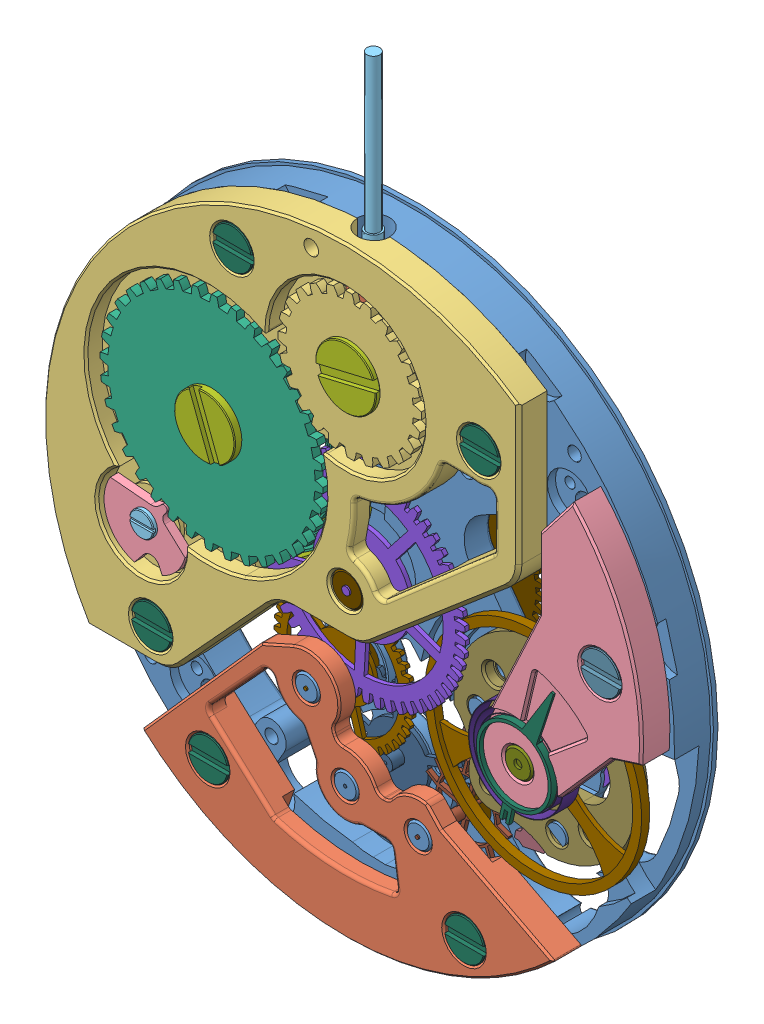
SolidWorks assembly watch movement eta-6497, configuration Default. Lengths in mm.
Overall size (37.71 45.6 5.66).
50 component instances, 38 part files, 89 mates.
Components (placement in the parent):
- MAIN_PLATE-scaled-1: MAIN_PLATE-scaled [Default] at origin size (37.71 36.6 2.78)
- TRAINWHEEL_BRIDGE-scaled-1: TRAINWHEEL_BRIDGE-scaled [Default] at (2.5344 36.3401 -7.4892) size (24.74 13.86 1.71)
- BARREL_BRIDGE-scaled-1: BARREL_BRIDGE-scaled [Default] at (14.8136 -19.5519 -6.5785) x (1 -0.000051 0) z (0 0 1) size (28.59 27.69 1.77)
- BALANCE_BRIDGE-scaled-1: BALANCE_BRIDGE-scaled [Default] at (-42.2984 -12.9016 -7.0972) x (1 0.000051 0) z (0 0 1) size (10.07 17.9 1.71)
- WINDING_STEM-scaled-1: WINDING_STEM-scaled [Default] at (10.0508 -68.8497 9.867) x (-0.408062 0 0.912954) z (-0.912954 0 -0.408062) size (1.01 15.96 1.01)
- RACHET_WHEEL-scaled-1: RACHET_WHEEL-scaled [Default] at (23.31 -20.3024 -7.9848) x (0.98772 -0.156233 0) z (0 0 1) size (13.44 13.44 0.48)
- RACHET_WHEEL_SCREW-scaled-1: RACHET_WHEEL_SCREW-scaled [Default] at (-12.6334 -35.0759 -7.5351) x (0.353105 -0.935584 0) z (0 0 1) size (3.66 3.66 2.6)
- DOUBLE_ROLLER-scaled-1: DOUBLE_ROLLER-scaled [Default] at (10.0823 -49.9696 1.6528) x (-0.365738 0.930718 0) z (0 0 1) size (5.37 5.37 2.36)
- BALANCE_WHEEL-scaled-1: BALANCE_WHEEL-scaled [Default] at (-30.3404 11.2366 -4.9178) x (0.999946 0.0104 0) z (0 0 1) size (13.07 13.07 0.49)
- DRIVER_CANNON_PINION-scaled-1: DRIVER_CANNON_PINION-scaled [Default] at (0.9212 -1.272 1.901) x (0.943007 0.332774 0) z (0 0 1) size (3.16 3.16 1.95)
- SETTING_LEVER_JUMPER-scaled-1: SETTING_LEVER_JUMPER-scaled [Default] at (-11.993 -30.3688 2.2117) x (0.999994 -0.00349 0) z (0 0 1) size (15.05 13.39 0.24)
- hour hand-1: hour hand [Default] at (0.9212 -1.272 2.9686) x (0.624696 0.780868 0) z (-0.780868 0.624696 0) size (13.45 0.48 2.7)
- minute hand-1: minute hand [Default] at (0.9212 -1.272 2.6686) x (0.738173 -0.674611 0) z (0.674611 0.738173 0) size (17.1 0.76 2.7)
- SETTING_LEVER-scaled-1: SETTING_LEVER-scaled [Default] at (11.0066 -49.5518 1.4696) x (1 -0.000174 0) z (0 0 1) size (6.14 4.36 0.49)
- REGULATOR-scaled-1: REGULATOR-scaled [Default] at (-30.7962 10.7464 -8.6033) size (4.64 8.34 0.37)
- JEWEL_BALANCE-scaled-1: JEWEL_BALANCE-scaled [Default] at (-30.1637 11.6689 -7.8137) size (1.71 1.71 0.37)
- hour wheel-40T-1: hour wheel-40T [Default] at (0.9212 -1.272 3.8344) x (0.652479 -0.757807 0) z (0.757807 0.652479 0) size (8.3 1.22 8.3)
- gear-2-1: gear-2 [Default] at (5.4157 1.075 4.2004) x (0.460007 -0.887915 0) z (0.887915 0.460007 0) size (8.2 0.64 8.2)
- 16T gear-1: 16T gear [Default] at (3.4604 6.3566 4.3224) x (0.960913 0.27685 0) z (-0.27685 0.960913 0) size (3.6 0.36 3.6)
- 16T gear-2: 16T gear [Default] at (0.9301 8.6353 4.3224) x (0.919979 0.391968 0) z (-0.391968 0.919979 0) size (3.6 0.36 3.6)
- SLIDING_PINION-scaled-1: SLIDING_PINION-scaled [Default] at (-5.9207 -44.3189 -1.5067) x (0.729303 0 -0.684191) z (0.684191 0 0.729303) size (2.32 2.18 2.32)
- CROWN_WHEEL-scaled-1: CROWN_WHEEL-scaled [Default] at (-12.6475 -33.666 -7.9811) x (0.955246 -0.295813 0) z (0 0 1) size (8.64 8.64 0.48)
- RACHET_WHEEL_SCREW-scaled-2: RACHET_WHEEL_SCREW-scaled [Default] at (38.2616 -0.2875 -7.7056) x (0.973191 0.229999 0) z (0 0 1) size (3.66 3.66 2.6)
- CLICK-scaled-1: CLICK-scaled [Default] at (36.7009 18.147 -7.9936) x (0.980467 0.196685 0) z (0 0 1) size (4.7 4.11 0.49)
- CLICK_SCREW-scaled-1: CLICK_SCREW-scaled [Default] at (38.9217 6.9981 -8.1965) size (1.46 1.46 1.76)
- main spring-1: main spring [Default] at (-7.394 3.1296 5.3464) x (0.236309 0.971678 0) z (-0.971678 0.236309 0) size (13.86 1.21 13.98)
- mainspring barrel-1: mainspring barrel [Default] at (-7.3704 3.2301 5.7464) x (-0.351757 0.936092 0) z (-0.936092 -0.351757 0) size (14.6 3.11 14.6)
- CENTER_WHEEL-scaled-1: CENTER_WHEEL-scaled [Default] at (0.9258 -1.2745 -6.2095) x (-0.613631 -0.789593 0) z (0 0 1) size (12.44 12.44 3.43)
- THIRD_WHEEL-scaled-1: THIRD_WHEEL-scaled [Default] at (-8.1014 18.875 -0.7426) x (0.821405 0.570345 0) z (0 0 1) size (8.36 8.35 4.26)
- SECOND_WHEEL-scaled-1: SECOND_WHEEL-scaled [Default] at (-33.5485 11.8646 -2.35) x (0.560513 0.828146 0) z (0 0 1) size (8.36 8.35 4.13)
- ESCAPE_WHEEL-scaled-1: ESCAPE_WHEEL-scaled [Default] at (51.8113 -4.9013 -0.1956) x (-0.243002 -0.970026 0) z (0 0 1) size (5.04 5.04 4.35)
- PALLET_BRIDGE-scaled-1: PALLET_BRIDGE-scaled [Default] at (-30.2397 10.7159 -2.3711) x (0.999995 -0.003169 0) z (0 0 1) size (10.97 10.97 1.46)
- PALLET_FORK-scaled-1: PALLET_FORK-scaled [Default] at (-24.7287 18.9965 0.4657) x (0.990636 0.136529 0) z (0 0 1) size (5.68 6.43 0.24)
- BALANCE_SCREW-scaled-1: BALANCE_SCREW-scaled [Default] at (-46.6067 -11.7285 -5.7239) size (2.44 2.44 3.57)
- BARREL_BRIDGE_SCREW-scaled-1: BARREL_BRIDGE_SCREW-scaled [Default] at (56.8731 41.5159 -5.7239) size (2.44 2.44 3.57)
- BARREL_BRIDGE_SCREW-scaled-2: BARREL_BRIDGE_SCREW-scaled [Default] at (42.0185 44.6227 -5.7239) size (2.44 2.44 3.57)
- BARREL_BRIDGE_SCREW-scaled-3: BARREL_BRIDGE_SCREW-scaled [Default] at (37.1325 22.4971 -5.7239) size (2.44 2.44 3.57)
- BARREL_BRIDGE_SCREW-scaled-4: BARREL_BRIDGE_SCREW-scaled [Default] at (55.983 15.5654 -5.7239) size (2.44 2.44 3.57)
- BARREL_BRIDGE_SCREW-scaled-5: BARREL_BRIDGE_SCREW-scaled [Default] at (40.5622 17.2734 -5.7239) size (2.44 2.44 3.57)
- bw shaft-1: bw shaft [Default] at (10.9539 -5.4487 3.9733) x (0.664459 -0.747325 0) z (-0.747325 -0.664459 0) size (0.49 3 0.49)
- balance spring-1: balance spring [Default] at (10.7982 -5.4568 7.0064) x (0.980374 -0.197147 0) z (-0.197147 -0.980374 0) size (5.76 1.01 5.91)
- JEWEL_MAIN-scaled-5: JEWEL_MAIN-scaled [Default] at (0.9205 -1.2722 -9.0684) size (1.95 1.95 0.37)
- JEWEL_MAIN-scaled-6: JEWEL_MAIN-scaled [Default] at (5.325 -11.8619 19.7871) x (0.901008 -0.433803 0) z (0 0 -1) size (1.95 1.95 0.37)
- JEWEL_MAIN-scaled-7: JEWEL_MAIN-scaled [Default] at (0.9309 -11.4243 19.7871) x (-0.858855 0.512218 0) z (0 0 -1) size (1.95 1.95 0.37)
- JEWEL_MAIN-scaled-8: JEWEL_MAIN-scaled [Default] at (-1.4055 -7.4875 19.7871) x (-0.953158 -0.302473 0) z (0 0 -1) size (1.95 1.95 0.37)
- JEWEL_BALANCE-scaled-3: JEWEL_BALANCE-scaled [Default] at (11.1063 -53.465 18.2884) x (0.308361 0.95127 0) z (0 0 -1) size (1.71 1.71 0.37)
- jewel-trainwheel-4: jewel-trainwheel [Default] at (-1.4055 -7.4875 7.4944) x (0.887598 0.460619 0) z (0 0 -1) size (1.5 1.5 0.4)
- jewel-trainwheel-5: jewel-trainwheel [Default] at (0.9308 -11.4243 7.4944) x (0.966485 0.256724 0) z (0 0 -1) size (1.5 1.5 0.4)
- jewel-trainwheel-6: jewel-trainwheel [Default] at (5.325 -11.8619 7.4944) x (0.902621 0.430435 0) z (0 0 -1) size (1.5 1.5 0.4)
- shaft-2-1: shaft-2 [Default] at (7.4813 -9.0714 5.3464) x (-0.704887 0.70932 0) z (-0.70932 -0.704887 0) size (0.4 2 0.4)
Mates (geometry in assembly coordinates):
- Coincident1: coincident anti-aligned: plane of MAIN_PLATE-scaled-1 through (-11.904 -5.8961 5.7864) normal (0 0 1); plane of BARREL_BRIDGE-scaled-1 through (-17.3872 -10.8229 5.7864) normal (0 0 -1)
- Concentric1: concentric aligned: cylinder of MAIN_PLATE-scaled-1 through (8.9738 10.0757 4.0784) axis (0 0 1) radius 0.4392; cylinder of BARREL_BRIDGE-scaled-1 through (8.9731 10.0759 5.7864) axis (0 0 1) radius 0.4392
- Concentric2: concentric aligned: cylinder of MAIN_PLATE-scaled-1 through (-5.8815 13.1827 4.0784) axis (0 0 1) radius 0.4821; cylinder of BARREL_BRIDGE-scaled-1 through (-5.8815 13.1827 5.7864) axis (0 0 1) radius 0.4392
- Coincident2: coincident anti-aligned: plane of MAIN_PLATE-scaled-1 through (-17.4172 -19.5383 5.7864) normal (0 0 1); plane of TRAINWHEEL_BRIDGE-scaled-1 through (-11.3594 -18.3746 5.7864) normal (0 0 -1)
- Concentric3: concentric aligned: cylinder of MAIN_PLATE-scaled-1 through (-7.3378 -14.1666 3.3464) axis (0 0 1) radius 0.4392; cylinder of TRAINWHEEL_BRIDGE-scaled-1 through (-7.3378 -14.1666 5.7864) axis (0 0 1) radius 0.4392
- Concentric4: concentric aligned: cylinder of MAIN_PLATE-scaled-1 through (8.083 -15.8746 3.3464) axis (0 0 1) radius 0.4392; cylinder of TRAINWHEEL_BRIDGE-scaled-1 through (8.083 -15.8746 5.7864) axis (0 0 1) radius 0.4392
- Coincident3: coincident anti-aligned: plane of MAIN_PLATE-scaled-1 through (-11.904 -5.8961 5.7864) normal (0 0 1); plane of BALANCE_BRIDGE-scaled-1 through (11.6238 -2.1978 5.7864) normal (0 0 -1)
- Concentric5: concentric aligned: cylinder of MAIN_PLATE-scaled-1 through (16.2609 2.104 3.3464) axis (0 0 1) radius 0.4518; cylinder of BALANCE_BRIDGE-scaled-1 through (16.2606 2.1034 5.7864) axis (0 0 1) radius 0.7823
- Concentric7: concentric aligned: cylinder of WINDING_STEM-scaled-1 through (0.9212 14.8036 5.7864) axis (0 1 0) radius 0.4854; cylinder of MAIN_PLATE-scaled-1 through (0.9212 14.5407 5.7864) axis (0 1 0) radius 0.976
- Concentric8: concentric anti-aligned: cylinder of BARREL_BRIDGE-scaled-1 through (-7.3704 3.2301 5.7864) axis (0 0 1) radius 1.2007; cylinder of RACHET_WHEEL-scaled-1 through (-7.3704 3.2301 7.2424) axis (0 0 -1) radius 1.8
- Concentric9: concentric aligned: cylinder of RACHET_WHEEL-scaled-1 through (-7.3704 3.2301 7.2424) axis (0 0 -1) radius 1.8; cylinder of RACHET_WHEEL_SCREW-scaled-1 through (-7.3704 3.2301 7.6209) axis (0 0 -1) radius 1.83
- Concentric10: concentric anti-aligned: cylinder of MAIN_PLATE-scaled-1 through (10.9539 -5.4487 4.0784) axis (0 0 -1) radius 0.8396; cylinder of DOUBLE_ROLLER-scaled-1 through (10.9539 -5.4487 3.8694) axis (0 0 1) radius 0.6665
- Concentric11: concentric aligned: cylinder of DOUBLE_ROLLER-scaled-1 through (10.9539 -5.4487 5.0443) axis (0 0 1) radius 1.1591; cylinder of BALANCE_WHEEL-scaled-1 through (10.9539 -5.4487 5.7221) axis (0 0 1) radius 0.2029
- Coincident6: coincident anti-aligned: plane of DOUBLE_ROLLER-scaled-1 through (12.4742 -6.1116 5.7221) normal (0 0 1); plane of BALANCE_WHEEL-scaled-1 through (4.4084 -12.1318 5.7221) normal (0 0 -1)
- Concentric12: concentric aligned: cylinder of MAIN_PLATE-scaled-1 through (0.9212 -1.272 4.3224) axis (0 0 1) radius 0.5072; cylinder of DRIVER_CANNON_PINION-scaled-1 through (0.9212 -1.272 3.6531) axis (0 0 1) radius 0.6539
- Coincident7: coincident anti-aligned: plane of MAIN_PLATE-scaled-1 through (2.9241 -3.275 4.3224) normal (0 0 -1); plane of DRIVER_CANNON_PINION-scaled-1 through (2.9588 -2.2466 4.3224) normal (0 0 1)
- Concentric15: concentric aligned: cylinder of MAIN_PLATE-scaled-1 through (6.5642 7.0405 3.8344) axis (0 0 1) radius 0.4707; circle of SETTING_LEVER_JUMPER-scaled-1
- Coincident9: coincident anti-aligned: plane of MAIN_PLATE-scaled-1 through (10.0896 3.6434 3.8344) normal (0 0 -1); plane of SETTING_LEVER_JUMPER-scaled-1 through (11.7473 1.2487 3.8344) normal (0 0 1)
- Concentric16: concentric anti-aligned: cylinder of MAIN_PLATE-scaled-1 through (10.9539 -5.4487 4.0784) axis (0 0 -1) radius 0.8396; cylinder of BALANCE_BRIDGE-scaled-1 through (10.9539 -5.4487 6.7624) axis (0 0 1) radius 0.859
- Concentric18: concentric aligned: cylinder of DRIVER_CANNON_PINION-scaled-1 through (0.9212 -1.272 2.3686) axis (0 0 1) radius 0.3411; cylinder of minute hand-1 through (0.9212 -1.272 2.3686) axis (0 0 1) radius 0.34
- Coincident11: coincident aligned: plane of DRIVER_CANNON_PINION-scaled-1 through (1.3616 -1.4826 2.3686) normal (0 0 -1); plane of minute hand-1 through (11.9104 -10.8013 2.3686) normal (0 0 -1)
- Coincident12: coincident anti-aligned: plane of SETTING_LEVER_JUMPER-scaled-1 through (11.7473 1.2487 3.8344) normal (0 0 1); plane of SETTING_LEVER-scaled-1 through (-1.8442 14.4894 3.8344) normal (0 0 -1)
- Concentric19: concentric anti-aligned: cylinder of MAIN_PLATE-scaled-1 through (-1.1083 15.6219 4.0784) axis (0 0 1) radius 0.4527; cylinder of SETTING_LEVER-scaled-1 through (-1.1083 15.6219 4.0784) axis (0 0 -1) radius 0.488
- Coincident13: coincident anti-aligned: plane of BALANCE_BRIDGE-scaled-1 through (11.5699 -3.6889 7.2504) normal (0 0 1); plane of REGULATOR-scaled-1 through (12.7329 -1.6663 7.2504) normal (0 0 -1)
- Concentric20: concentric aligned: cylinder of BALANCE_BRIDGE-scaled-1 through (10.9539 -5.4487 6.7624) axis (0 0 1) radius 0.859; cylinder of REGULATOR-scaled-1 through (10.9539 -5.4487 7.0064) axis (0 0 1) radius 2.074
- Concentric21: concentric aligned: cylinder of BALANCE_BRIDGE-scaled-1 through (10.9539 -5.4487 6.7624) axis (0 0 1) radius 0.859; cylinder of JEWEL_BALANCE-scaled-1 through (10.9539 -5.4487 6.7624) axis (0 0 1) radius 0.854
- Coincident14: coincident aligned: plane of BALANCE_BRIDGE-scaled-1 through (8.8552 -7.5477 7.1284) normal (0 0 1); plane of JEWEL_BALANCE-scaled-1 through (10.9539 -5.4487 7.1284) normal (0 0 1)
- Coincident15: coincident anti-aligned: plane of MAIN_PLATE-scaled-1 through (5.2754 -6.0483 3.8344) normal (0 0 -1); plane of hour wheel-40T-1 through (0.9212 -1.272 3.8344) normal (0 0 1)
- Concentric22: concentric anti-aligned: cylinder of DRIVER_CANNON_PINION-scaled-1 through (0.9212 -1.272 3.6531) axis (0 0 1) radius 0.6539; cylinder of hour wheel-40T-1 through (0.9212 -1.272 3.8344) axis (0 0 -1) radius 0.73
- Coincident16: coincident anti-aligned: plane of MAIN_PLATE-scaled-1 through (9.7641 -3.2735 4.2004) normal (0 0 -1); plane of gear-2-1 through (5.4157 1.075 4.2004) normal (0 0 1)
- Concentric23: concentric aligned: cylinder of MAIN_PLATE-scaled-1 through (5.4157 1.075 4.2004) axis (0 0 -1) radius 0.6653; cylinder of gear-2-1 through (5.4157 1.075 4.2004) axis (0 0 -1) radius 0.5
- Concentric24: concentric aligned: cylinder of hour hand-1 through (0.9212 -1.272 2.6686) axis (0 0 1) radius 0.93; cylinder of hour wheel-40T-1 through (0.9212 -1.272 2.6144) axis (0 0 1) radius 0.93
- Concentric25: concentric aligned: cylinder of MAIN_PLATE-scaled-1 through (3.4604 6.3566 4.3224) axis (0 0 -1) radius 0.4392; cylinder of 16T gear-1 through (3.4604 6.3566 4.3224) axis (0 0 -1) radius 0.44
- Coincident17: coincident anti-aligned: plane of MAIN_PLATE-scaled-1 through (5.62 4.2013 4.3224) normal (0 0 -1); plane of 16T gear-1 through (3.4604 6.3566 4.3224) normal (0 0 1)
- Concentric26: concentric aligned: cylinder of MAIN_PLATE-scaled-1 through (0.9301 8.6353 4.3224) axis (0 0 -1) radius 0.4392; cylinder of 16T gear-2 through (0.9301 8.6353 4.3224) axis (0 0 -1) radius 0.44
- Coincident18: coincident aligned: plane of 16T gear-1 through (3.4604 6.3566 3.9624) normal (0 0 -1); plane of 16T gear-2 through (0.9301 8.6353 3.9624) normal (0 0 -1)
- Concentric27: concentric aligned: cylinder of WINDING_STEM-scaled-1 through (0.9212 11.008 5.7864) axis (0 1 0) radius 0.2436; cylinder of SLIDING_PINION-scaled-1 through (0.9212 12.0782 5.7864) axis (0 1 0) radius 0.342
- Concentric28: concentric aligned: cylinder of BARREL_BRIDGE-scaled-1 through (0.9491 9.8525 5.7864) axis (0 0 1) radius 0.622; cylinder of CROWN_WHEEL-scaled-1 through (0.9491 9.8525 6.7624) axis (0 0 1) radius 1.0841
- Coincident19: coincident aligned: plane of RACHET_WHEEL-scaled-1 through (-15.1485 -2.4235 7.2424) normal (0 0 1); plane of CROWN_WHEEL-scaled-1 through (0.9491 9.8525 7.2424) normal (0 0 1)
- Coincident20: coincident anti-aligned: plane of BARREL_BRIDGE-scaled-1 through (-12.8023 -2.2021 6.7624) normal (0 0 1); plane of RACHET_WHEEL-scaled-1 through (-15.1485 -2.4235 6.7624) normal (0 0 -1)
- Concentric29: concentric anti-aligned: cylinder of BARREL_BRIDGE-scaled-1 through (0.9491 9.8525 5.7864) axis (0 0 1) radius 0.622; cylinder of RACHET_WHEEL_SCREW-scaled-2 through (0.9491 9.8525 7.0112) axis (0 0 -1) radius 0.488
- Concentric30: concentric aligned: cylinder of BARREL_BRIDGE-scaled-1 through (-11.3446 -3.9406 6.7624) axis (0 0 1) radius 0.6582; cylinder of CLICK-scaled-1 through (-11.3446 -3.9406 6.7624) axis (0 0 1) radius 0.7292
- Coincident21: coincident anti-aligned: plane of BARREL_BRIDGE-scaled-1 through (-13.004 -5.5998 6.7624) normal (0 0 1); plane of CLICK-scaled-1 through (-11.4397 -4.3432 6.7624) normal (0 0 -1)
- Concentric31: concentric anti-aligned: cylinder of BARREL_BRIDGE-scaled-1 through (-11.3446 -3.9406 5.7864) axis (0 0 1) radius 0.4142; cylinder of CLICK_SCREW-scaled-1 through (-11.3446 -3.9406 6.5709) axis (0 0 -1) radius 0.2087
- Coincident22: coincident anti-aligned: plane of BARREL_BRIDGE-scaled-1 through (-12.0107 -4.6066 7.2504) normal (0 0 1); plane of CLICK_SCREW-scaled-1 through (-10.8742 -3.9406 7.2504) normal (0 0 -1)
- Concentric32: concentric anti-aligned: cylinder of BARREL_BRIDGE-scaled-1 through (-7.3704 3.2301 5.7864) axis (0 0 1) radius 1.2007; cylinder of mainspring barrel-1 through (-7.3704 3.2301 7.3464) axis (0 0 -1) radius 1.2
- Distance1: distance = 0.9 mm aligned: plane of mainspring barrel-1 through (-7.3704 3.2301 4.2464) normal (0 0 -1); plane of MAIN_PLATE-scaled-1 through (-17.5984 -19.7916 3.3464) normal (0 0 -1)
- Coincident27: coincident: line of main spring-1 through (-14.1958 4.7838 4.3964) axis (0 0 1); cylinder of mainspring barrel-1 through (-7.3704 3.2301 5.7464) axis (0 0 -1) radius 7
- Coincident28: coincident anti-aligned: plane of main spring-1 through (-14.0986 4.7602 4.3464) normal (0 0 -1); plane of mainspring barrel-1 through (-7.3704 3.2301 4.3464) normal (0 0 1)
- Concentric33: concentric aligned: cylinder of BARREL_BRIDGE-scaled-1 through (0.9205 -1.2722 7.3724) axis (0 0 -1) radius 0.976; cylinder of CENTER_WHEEL-scaled-1 through (0.9205 -1.2722 6.2275) axis (0 0 -1) radius 1.22
- Concentric35: concentric anti-aligned: cylinder of TRAINWHEEL_BRIDGE-scaled-1 through (-1.4055 -7.4875 7.3724) axis (0 0 -1) radius 0.732; cylinder of THIRD_WHEEL-scaled-1 through (-1.4055 -7.4875 6.6959) axis (0 0 1) radius 0.4398
- Concentric43: concentric anti-aligned: cylinder of TRAINWHEEL_BRIDGE-scaled-1 through (0.9308 -11.4243 7.3724) axis (0 0 -1) radius 0.732; cylinder of SECOND_WHEEL-scaled-1 through (0.9308 -11.4243 4.3481) axis (0 0 1) radius 0.4392
- Concentric44: concentric aligned: cylinder of TRAINWHEEL_BRIDGE-scaled-1 through (5.325 -11.8619 7.3724) axis (0 0 -1) radius 0.732; cylinder of ESCAPE_WHEEL-scaled-1 through (5.325 -11.8619 5.9361) axis (0 0 -1) radius 0.3281
- Concentric45: concentric aligned: cylinder of MAIN_PLATE-scaled-1 through (7.8501 -3.1743 3.3464) axis (0 0 1) radius 0.4848; cylinder of PALLET_BRIDGE-scaled-1 through (7.8501 -3.1743 4.7567) axis (0 0 1) radius 0.488
- Concentric47: concentric aligned: cylinder of PALLET_BRIDGE-scaled-1 through (7.4813 -9.0714 4.7567) axis (0 0 1) radius 0.488; cylinder of PALLET_FORK-scaled-1 through (7.4813 -9.0714 4.3437) axis (0 0 1) radius 0.2031
- Concentric48: concentric anti-aligned: cylinder of MAIN_PLATE-scaled-1 through (16.2609 2.104 3.3464) axis (0 0 1) radius 0.4518; cylinder of BALANCE_SCREW-scaled-1 through (16.2609 2.104 5.2203) axis (0 0 -1) radius 0.6196
- Coincident37: coincident anti-aligned: plane of BALANCE_BRIDGE-scaled-1 through (15.026 0.8687 6.2744) normal (0 0 1); plane of BALANCE_SCREW-scaled-1 through (17.1807 2.104 6.2744) normal (0 0 -1)
- Concentric49: concentric anti-aligned: cylinder of BARREL_BRIDGE-scaled-1 through (8.9731 10.0759 5.7864) axis (0 0 1) radius 0.4392; cylinder of BARREL_BRIDGE_SCREW-scaled-1 through (8.9731 10.0759 5.2203) axis (0 0 -1) radius 0.6196
- Coincident38: coincident anti-aligned: plane of BARREL_BRIDGE-scaled-1 through (7.7384 8.8413 6.2744) normal (0 0 1); plane of BARREL_BRIDGE_SCREW-scaled-1 through (9.8929 10.0759 6.2744) normal (0 0 -1)
- Concentric50: concentric anti-aligned: cylinder of BARREL_BRIDGE-scaled-1 through (-5.8815 13.1827 5.7864) axis (0 0 1) radius 0.4392; cylinder of BARREL_BRIDGE_SCREW-scaled-2 through (-5.8815 13.1827 5.2203) axis (0 0 -1) radius 0.6196
- Coincident39: coincident anti-aligned: plane of BARREL_BRIDGE-scaled-1 through (-7.1162 11.9482 6.2744) normal (0 0 1); plane of BARREL_BRIDGE_SCREW-scaled-2 through (-4.9617 13.1827 6.2744) normal (0 0 -1)
- Concentric51: concentric anti-aligned: cylinder of BARREL_BRIDGE-scaled-1 through (-10.7675 -8.9429 5.7864) axis (0 0 1) radius 0.4392; cylinder of BARREL_BRIDGE_SCREW-scaled-3 through (-10.7675 -8.9429 5.2203) axis (0 0 -1) radius 0.6196
- Coincident40: coincident anti-aligned: plane of BARREL_BRIDGE-scaled-1 through (-12.0022 -10.1775 6.2744) normal (0 0 1); plane of BARREL_BRIDGE_SCREW-scaled-3 through (-9.8477 -8.9429 6.2744) normal (0 0 -1)
- Concentric52: concentric anti-aligned: cylinder of TRAINWHEEL_BRIDGE-scaled-1 through (8.083 -15.8746 5.7864) axis (0 0 1) radius 0.4392; cylinder of BARREL_BRIDGE_SCREW-scaled-4 through (8.083 -15.8746 5.2203) axis (0 0 -1) radius 0.6196
- Coincident41: coincident anti-aligned: plane of TRAINWHEEL_BRIDGE-scaled-1 through (6.8484 -17.1092 6.2744) normal (0 0 1); plane of BARREL_BRIDGE_SCREW-scaled-4 through (9.0028 -15.8746 6.2744) normal (0 0 -1)
- Concentric53: concentric anti-aligned: cylinder of TRAINWHEEL_BRIDGE-scaled-1 through (-7.3378 -14.1666 5.7864) axis (0 0 1) radius 0.4392; cylinder of BARREL_BRIDGE_SCREW-scaled-5 through (-7.3378 -14.1666 5.2203) axis (0 0 -1) radius 0.6196
- Coincident42: coincident anti-aligned: plane of TRAINWHEEL_BRIDGE-scaled-1 through (-8.5724 -15.4012 6.2744) normal (0 0 1); plane of BARREL_BRIDGE_SCREW-scaled-5 through (-6.418 -14.1666 6.2744) normal (0 0 -1)
- Concentric55: concentric anti-aligned: cylinder of JEWEL_BALANCE-scaled-1 through (10.9539 -5.4487 6.7624) axis (0 0 1) radius 0.244; cylinder of bw shaft-1 through (10.9539 -5.4487 6.9733) axis (0 0 -1) radius 0.245
- Coincident44: coincident anti-aligned: plane of hour hand-1 through (7.4484 7.3814 2.6686) normal (0 0 -1); plane of minute hand-1 through (11.9104 -10.8013 2.6686) normal (0 0 1)
- Coincident45: coincident anti-aligned: plane of REGULATOR-scaled-1 through (11.5537 -4.3136 7.0064) normal (0 0 -1); plane of balance spring-1 through (10.2068 -8.3979 7.0064) normal (0 0 1)
- Coincident46: coincident aligned: plane of REGULATOR-scaled-1 through (10.1959 -8.4477 7.2504) normal (0.977112 -0.212723 0); plane of balance spring-1 through (10.21 -8.3833 7.0064) normal (0.977112 -0.212723 0)
- Concentric57: concentric anti-aligned: cylinder of BARREL_BRIDGE-scaled-1 through (0.9205 -1.2722 7.3724) axis (0 0 -1) radius 0.976; cylinder of JEWEL_MAIN-scaled-5 through (0.9205 -1.2722 7.0064) axis (0 0 1) radius 0.976
- Concentric58: concentric aligned: cylinder of MAIN_PLATE-scaled-1 through (5.325 -11.8619 4.3464) axis (0 0 -1) radius 0.975; cylinder of JEWEL_MAIN-scaled-6 through (5.325 -11.8619 3.7124) axis (0 0 -1) radius 0.976
- Coincident48: coincident aligned: plane of MAIN_PLATE-scaled-1 through (-17.5984 -19.7916 3.3464) normal (0 0 -1); plane of JEWEL_MAIN-scaled-6 through (5.325 -11.8619 3.3464) normal (0 0 -1)
- Concentric60: concentric aligned: cylinder of MAIN_PLATE-scaled-1 through (0.9309 -11.4243 4.3464) axis (0 0 -1) radius 0.975; cylinder of JEWEL_MAIN-scaled-7 through (0.9309 -11.4243 3.7124) axis (0 0 -1) radius 0.976
- Coincident49: coincident aligned: plane of MAIN_PLATE-scaled-1 through (-17.5984 -19.7916 3.3464) normal (0 0 -1); plane of JEWEL_MAIN-scaled-7 through (0.9309 -11.4243 3.3464) normal (0 0 -1)
- Concentric61: concentric aligned: cylinder of MAIN_PLATE-scaled-1 through (-1.4055 -7.4875 4.3464) axis (0 0 -1) radius 0.975; cylinder of JEWEL_MAIN-scaled-8 through (-1.4055 -7.4875 3.7124) axis (0 0 -1) radius 0.976
- Coincident50: coincident aligned: plane of MAIN_PLATE-scaled-1 through (-17.5984 -19.7916 3.3464) normal (0 0 -1); plane of JEWEL_MAIN-scaled-8 through (-1.4055 -7.4875 3.3464) normal (0 0 -1)
- Concentric63: concentric aligned: cylinder of MAIN_PLATE-scaled-1 through (7.502 -9.0726 5.8415) axis (0 0 -1) radius 0.855; cylinder of JEWEL_BALANCE-scaled-3 through (7.502 -9.0726 3.7124) axis (0 0 -1) radius 0.854
- Coincident51: coincident aligned: plane of MAIN_PLATE-scaled-1 through (-17.5984 -19.7916 3.3464) normal (0 0 -1); plane of JEWEL_BALANCE-scaled-3 through (7.502 -9.0726 3.3464) normal (0 0 -1)
- Concentric65: concentric anti-aligned: cylinder of TRAINWHEEL_BRIDGE-scaled-1 through (-1.4055 -7.4875 7.3724) axis (0 0 -1) radius 0.732; cylinder of jewel-trainwheel-4 through (-1.4055 -7.4875 7.0944) axis (0 0 1) radius 0.75
- Coincident52: coincident aligned: plane of TRAINWHEEL_BRIDGE-scaled-1 through (-11.2874 -19.3119 7.4944) normal (0 0 1); plane of jewel-trainwheel-4 through (-1.4055 -7.4875 7.4944) normal (0 0 1)
- Concentric66: concentric anti-aligned: cylinder of TRAINWHEEL_BRIDGE-scaled-1 through (0.9308 -11.4243 7.3724) axis (0 0 -1) radius 0.732; cylinder of jewel-trainwheel-5 through (0.9308 -11.4243 7.0944) axis (0 0 1) radius 0.75
- Coincident53: coincident aligned: plane of TRAINWHEEL_BRIDGE-scaled-1 through (-11.2874 -19.3119 7.4944) normal (0 0 1); plane of jewel-trainwheel-5 through (0.9308 -11.4243 7.4944) normal (0 0 1)
- Concentric67: concentric anti-aligned: cylinder of TRAINWHEEL_BRIDGE-scaled-1 through (5.325 -11.8619 7.3724) axis (0 0 -1) radius 0.732; cylinder of jewel-trainwheel-6 through (5.325 -11.8619 7.0944) axis (0 0 1) radius 0.75
- Coincident54: coincident aligned: plane of TRAINWHEEL_BRIDGE-scaled-1 through (-11.2874 -19.3119 7.4944) normal (0 0 1); plane of jewel-trainwheel-6 through (5.325 -11.8619 7.4944) normal (0 0 1)
- Concentric68: concentric aligned: cylinder of PALLET_FORK-scaled-1 through (7.4813 -9.0714 4.3437) axis (0 0 1) radius 0.2031; cylinder of shaft-2-1 through (7.4813 -9.0714 3.3464) axis (0 0 1) radius 0.2
- Concentric69: concentric aligned: cylinder of PALLET_BRIDGE-scaled-1 through (7.4813 -9.0714 4.7567) axis (0 0 1) radius 0.488; cylinder of PALLET_FORK-scaled-1 through (7.4813 -9.0714 4.3437) axis (0 0 1) radius 0.2031
- Coincident55: coincident aligned: plane of MAIN_PLATE-scaled-1 through (-17.5984 -19.7916 3.3464) normal (0 0 -1); plane of shaft-2-1 through (7.4813 -9.0714 3.3464) normal (0 0 -1)
